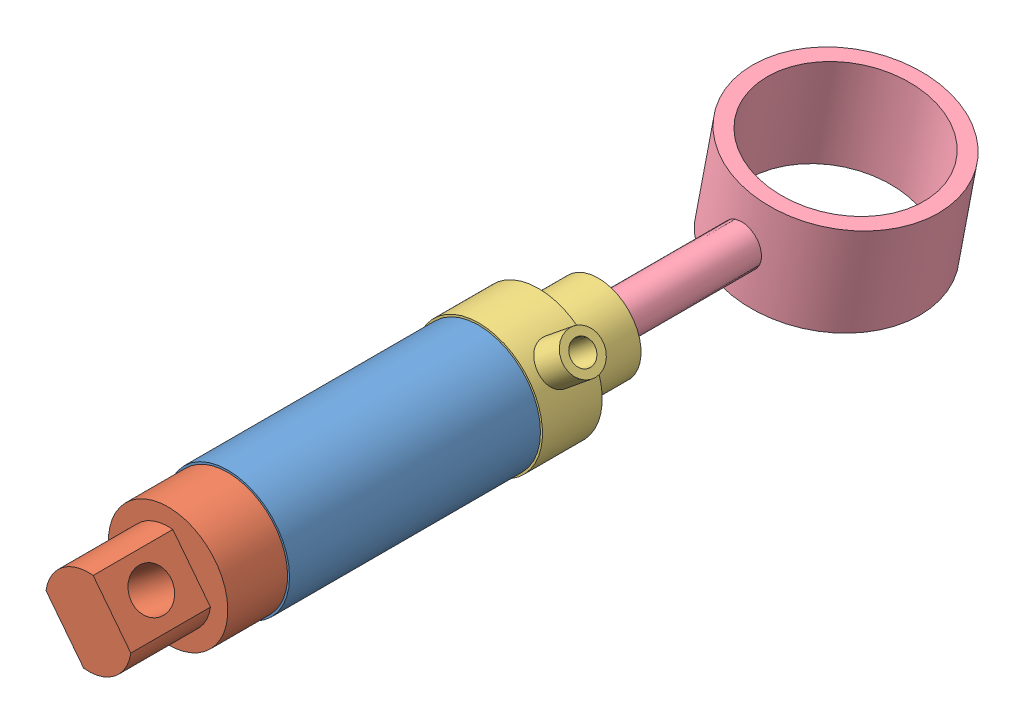
SolidWorks assembly Assem2, configuration Default. Lengths in mm.
Overall size (54.81 50.06 211.5).
4 component instances, 4 part files, 6 mates.
Components (placement in the parent):
- cylender 2nd piston-1: cylender 2nd piston [Default] at (22.2997 35.485 15.7279) size (31 31 63)
- 2nd piston end part-1: 2nd piston end part [Default] at (22.2997 35.485 113.7279) x (0 0 -1) z (0.789291 0.614019 0) size (39 30 30)
- 2nd piston start point-1: 2nd piston start point [Default] at (22.2997 35.485 -14.2721) x (0 0 1) z (-0.630478 0.776207 0) size (34 40 32)
- 2nd part piston-1: 2nd part piston [Default] at (22.2997 35.485 -50.2721) x (0 0 1) z (-0.98223 0.18768 0) size (122.5 29.5 47.5)
Mates (geometry in assembly coordinates):
- Coincident1: coincident: plane of cylender 2nd piston-1 through (22.2997 35.485 78.7279) normal (0 0 1); plane of 2nd piston end part-1 through (13.0894 47.3244 78.7279) normal (0 0 -1)
- Concentric1: concentric: cylinder of cylender 2nd piston-1 through (22.2997 35.485 78.7279) axis (0 0 -1) radius 15.5; cylinder of 2nd piston end part-1 through (22.2997 35.485 78.7279) axis (0 0 -1) radius 15
- Concentric2: concentric: cylinder of cylender 2nd piston-1 through (22.2997 35.485 78.7279) axis (0 0 -1) radius 15.5; cylinder of 2nd piston start point-1 through (22.2997 35.485 -14.2721) axis (0 0 -1) radius 16
- Coincident2: coincident: plane of cylender 2nd piston-1 through (22.2997 35.485 15.7279) normal (0 0 -1); plane of 2nd piston start point-1 through (34.719 45.5727 15.7279) normal (0 0 1)
- Concentric3: concentric: cylinder of cylender 2nd piston-1 through (22.2997 35.485 78.7279) axis (0 0 -1) radius 15.5; cylinder of 2nd part piston-1 through (22.2997 35.485 24.7279) axis (0 0 1) radius 5
- LimitDistance1: limit distance = 50 mm: plane of 2nd part piston-1 through (25.068 49.9729 24.7279) normal (0 0 1); plane of 2nd piston end part-1 through (22.2997 35.485 74.7279) normal (0 0 -1)
